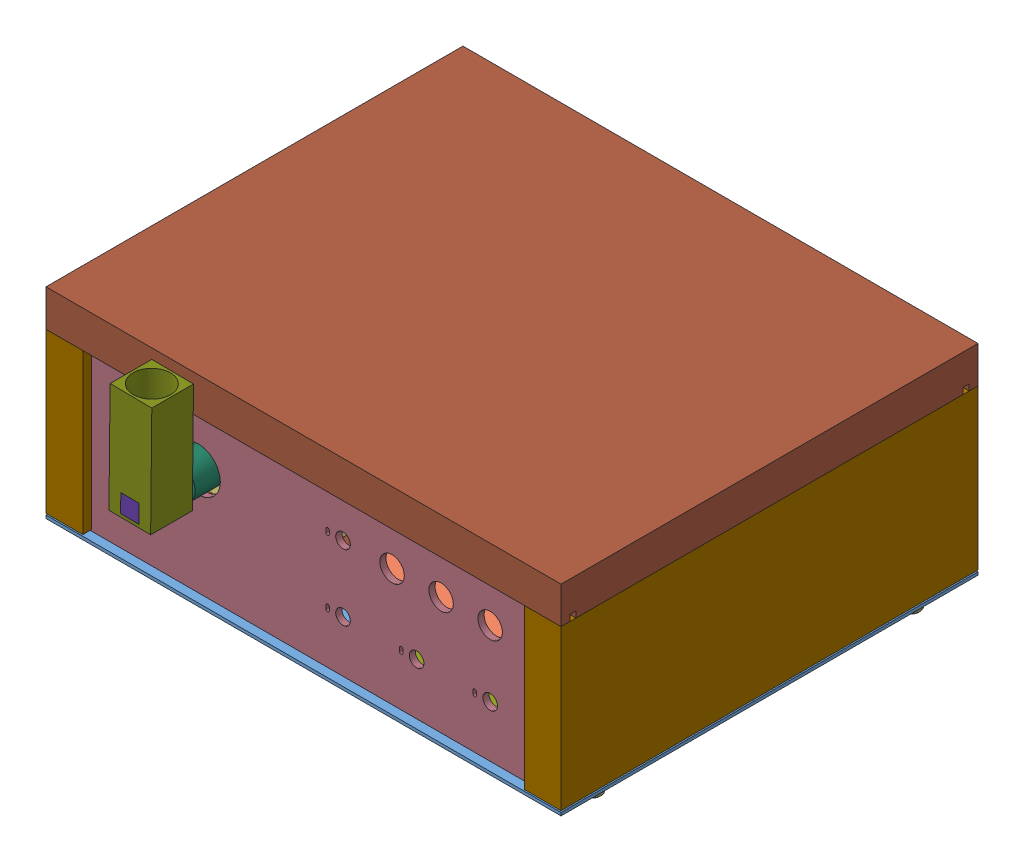
SolidWorks assembly Enclosure Assembly, configuration Default. Lengths in mm.
Overall size (266.7 114.51 246.61).
44 component instances, 21 part files, 71 mates.
Components (placement in the parent):
- Base Plate-1: Base Plate [Default] at (95.1379 143.2201 188.081) size (266.7 1.57 215.9)
- Driver Block-1: Driver Block [Default] at (35.9559 143.2201 203.5115) x (0 0 -1) z (1 0 0) size (130.18 25.4 76.2)
- Motor Mounting Assembly-1: Motor Mounting Assembly [Default] at (35.2898 189.415 201.5637) x (0 0 1) z (-1 0 0) size (444.54 56.1 76.2)
  - Motor Mount-1: Motor Mount [Default] at (1.9479 -20.7949 -0.6662) size (130.18 50.38 76.2)
  - Maxon Motor-1: Maxon Motor [Default] at (62.8204 9.2051 -0.6662) x (-1 0 0) z (0 0 -1) size (96.7 30 30)
  - Encoder Block-1: Encoder Block [Default] at (-24.3646 9.2051 -0.6662) x (0 0.000323 1) z (1 0 0) size (30 41.1 18.3)
  - 91274A103_Zinc-Aluminum-Coated Alloy Steel Socket Head Screw-1: 91274A103_Zinc-Aluminum-Coated Alloy Steel Socket Head Screw [91274A103] at (59.0354 20.2051 -0.6662) x (0 -0.151827 -0.988407) z (-1 0 0) size (5.5 5.5 11.2)
  - 91274A103_Zinc-Aluminum-Coated Alloy Steel Socket Head Screw-2: 91274A103_Zinc-Aluminum-Coated Alloy Steel Socket Head Screw [91274A103] at (59.0354 3.7051 8.8601) x (0 0 -1) z (-1 0 0) size (5.5 5.5 11.2)
  - 91274A103_Zinc-Aluminum-Coated Alloy Steel Socket Head Screw-3: 91274A103_Zinc-Aluminum-Coated Alloy Steel Socket Head Screw [91274A103] at (59.0354 3.7051 -10.1924) x (0 0 -1) z (-1 0 0) size (5.5 5.5 11.2)
  - 91274A103_Zinc-Aluminum-Coated Alloy Steel Socket Head Screw-4: 91274A103_Zinc-Aluminum-Coated Alloy Steel Socket Head Screw [91274A103] at (59.0354 14.7051 8.8601) x (0 0 -1) z (-1 0 0) size (5.5 5.5 11.2)
  - 91274A103_Zinc-Aluminum-Coated Alloy Steel Socket Head Screw-5: 91274A103_Zinc-Aluminum-Coated Alloy Steel Socket Head Screw [91274A103] at (59.0354 14.7051 -10.1924) x (0 0 -1) z (-1 0 0) size (5.5 5.5 11.2)
  - 91274A103_Zinc-Aluminum-Coated Alloy Steel Socket Head Screw-6: 91274A103_Zinc-Aluminum-Coated Alloy Steel Socket Head Screw [91274A103] at (59.0354 -1.7949 -0.6662) x (0 0 -1) z (-1 0 0) size (5.5 5.5 11.2)
- Power Supply Block-1: Power Supply Block [Default] at (153.9988 143.2201 194.109) x (-0.000272 0 -1) z (1 0 -0.000272) size (158.75 38.1 98.42)
- myRio Block-1: myRio Block [Default] at (151.3206 184.4951 195.7743) x (0 0 -1) z (1 0 0) size (136.53 25.4 88.9)
- Wood Side Piece-1: Wood Side Piece [Default] at (-38.2121 185.2571 188.081) x (0 0 -1) z (1 0 0) size (215.9 82.55 19.05)
- Wood Side Piece-2: Wood Side Piece [Default] at (228.4879 185.2571 188.081) x (0 0 1) z (-1 0 0) size (215.9 82.55 19.05)
- 97467A725_18-8 Stainless Steel Heavy-Duty Rivet Nut-1: 97467A725_18-8 Stainless Steel Heavy-Duty Rivet Nut [97467A725] at (218.9629 143.2201 270.631) x (-0.837169 0 -0.546944) z (-0.546944 0 0.837169) size (12.7 16 12.7)
- 97467A725_18-8 Stainless Steel Heavy-Duty Rivet Nut-2: 97467A725_18-8 Stainless Steel Heavy-Duty Rivet Nut [97467A725] at (218.9629 143.2201 105.531) x (-0.837169 0 -0.546944) z (-0.546944 0 0.837169) size (12.7 16 12.7)
- 97467A725_18-8 Stainless Steel Heavy-Duty Rivet Nut-3: 97467A725_18-8 Stainless Steel Heavy-Duty Rivet Nut [97467A725] at (-28.6871 143.2201 270.631) x (-0.837169 0 -0.546944) z (-0.546944 0 0.837169) size (12.7 16 12.7)
- 97467A725_18-8 Stainless Steel Heavy-Duty Rivet Nut-4: 97467A725_18-8 Stainless Steel Heavy-Duty Rivet Nut [97467A725] at (-28.6871 143.2201 105.531) x (-0.36154 0 0.932356) z (0.932356 0 0.36154) size (12.7 16 12.7)
- Wood Top Piece-1: Wood Top Piece [Default] at (95.1379 226.5321 188.081) size (266.7 19.05 215.9)
- 91274A160_Zinc-Aluminum-Coated Alloy Steel Socket Head Screw-1: 91274A160_Zinc-Aluminum-Coated Alloy Steel Socket Head Screw [91274A160] at (218.9629 157.5203 105.531) x (-0.902068 0 0.431594) z (0 1 0) size (9.53 9.53 22.9)
- 91274A160_Zinc-Aluminum-Coated Alloy Steel Socket Head Screw-2: 91274A160_Zinc-Aluminum-Coated Alloy Steel Socket Head Screw [91274A160] at (218.9629 157.5203 270.631) x (-0.803937 0 -0.594714) z (0 1 0) size (9.53 9.53 22.9)
- 91274A160_Zinc-Aluminum-Coated Alloy Steel Socket Head Screw-3: 91274A160_Zinc-Aluminum-Coated Alloy Steel Socket Head Screw [91274A160] at (-28.6871 157.5203 270.631) x (-0.882264 0 -0.470755) z (0 1 0) size (9.53 9.53 22.9)
- 91274A160_Zinc-Aluminum-Coated Alloy Steel Socket Head Screw-4: 91274A160_Zinc-Aluminum-Coated Alloy Steel Socket Head Screw [91274A160] at (-28.6871 157.5203 105.531) x (-0.849031 0 -0.528343) z (0 1 0) size (9.53 9.53 22.9)
- Front and Back Piece-1: Front and Back Piece [Default] at (95.1379 186.4001 291.459) size (234.95 86.36 3.17)
- Back Piece-1: Back Piece [Default] at (95.1379 186.4001 84.703) x (-1 0 0) z (0 0 -1) size (234.95 86.36 3.17)
- Coupler-1: Coupler [Default] at (35.9559 198.6201 289.479) x (-0.99356 -0.113306 0) z (0 0 -1) size (18 18 25)
- Pendulum Assembly-1: Pendulum Assembly [Default] at (10.9481 174.972 253.8303) x (0.999944 -0.01058 0) z (0 0 1) size (21.59 57.15 44.45)
  - Pendulum-1: Pendulum [Default] at (24.7562 17.5613 62.1187) size (21.59 57.15 21.59)
  - Pendulum Dowel-1: Pendulum Dowel [Default] at (24.7562 23.9113 66.5637) size (9.53 9.53 44.45)
- 90272A163_Zinc-Plated Steel Pan Head Phillips Screw-1: 90272A163_Zinc-Plated Steel Pan Head Phillips Screw [90272A163] at (63.3879 178.5134 142.742) x (1 0 0) z (0 -1 0) size (6.86 6.86 79.08)
- 90272A163_Zinc-Plated Steel Pan Head Phillips Screw-2: 90272A163_Zinc-Plated Steel Pan Head Phillips Screw [90272A163] at (12.5879 178.5134 264.281) x (1 0 0) z (0 -1 0) size (6.86 6.86 79.08)
- 90272A163_Zinc-Plated Steel Pan Head Phillips Screw-3: 90272A163_Zinc-Plated Steel Pan Head Phillips Screw [90272A163] at (12.5879 178.5134 142.742) x (1 0 0) z (0 -1 0) size (6.86 6.86 79.08)
- 90272A163_Zinc-Plated Steel Pan Head Phillips Screw-4: 90272A163_Zinc-Plated Steel Pan Head Phillips Screw [90272A163] at (63.3879 178.5134 264.281) x (1 0 0) z (0 -1 0) size (6.86 6.86 79.08)
- 90631A007_Low-Strength Steel Nylon-Insert Locknut-1: 90631A007_Low-Strength Steel Nylon-Insert Locknut [90631A007] at (63.3879 188.6201 142.742) size (7.94 4.48 9.17)
- 90631A007_Low-Strength Steel Nylon-Insert Locknut-2: 90631A007_Low-Strength Steel Nylon-Insert Locknut [90631A007] at (12.5879 188.6201 264.281) size (7.94 4.48 9.17)
- 90631A007_Low-Strength Steel Nylon-Insert Locknut-3: 90631A007_Low-Strength Steel Nylon-Insert Locknut [90631A007] at (63.3879 188.6201 264.281) size (7.94 4.48 9.17)
- 90631A007_Low-Strength Steel Nylon-Insert Locknut-4: 90631A007_Low-Strength Steel Nylon-Insert Locknut [90631A007] at (12.5879 188.6201 142.742) size (7.94 4.48 9.17)
- myRIO_Mounting_Plate V2-1: myRIO_Mounting_Plate V2 [Default] at (150.8238 181.3201 194.1099) x (-0.000272 0 -1) z (1 0 -0.000272) size (165.1 9.65 104.77)
- 90272A163_Zinc-Plated Steel Pan Head Phillips Screw-5: 90272A163_Zinc-Plated Steel Pan Head Phillips Screw [90272A163] at (194.4879 178.5134 270.031) x (1 0 0) z (0 -1 0) size (6.86 6.86 79.08)
- 90272A163_Zinc-Plated Steel Pan Head Phillips Screw-6: 90272A163_Zinc-Plated Steel Pan Head Phillips Screw [90272A163] at (111.4879 178.5134 117.131) x (1 0 0) z (0 -1 0) size (6.86 6.86 79.08)
- 90675A007_Steel Locknut with External-Tooth Lock Washer-1: 90675A007_Steel Locknut with External-Tooth Lock Washer [90675A007] at (194.4879 186.2731 270.031) x (0.908918 0 -0.416976) z (0 1 0) size (8.75 9.15 3.68)
- 90675A007_Steel Locknut with External-Tooth Lock Washer-2: 90675A007_Steel Locknut with External-Tooth Lock Washer [90675A007] at (111.4684 186.2731 117.1536) x (-0.80754 0 0.589813) z (0 1 0) size (8.75 9.15 3.68)
Mates (geometry in assembly coordinates):
- Coincident1: coincident anti-aligned: plane of Base Plate-1 through (95.1379 143.2201 188.081) normal (0 1 0); plane of Driver Block-1 through (35.9559 143.2201 203.5115) normal (0 -1 0)
- Coincident2: coincident anti-aligned: plane of Base Plate-1 through (95.1379 143.2201 188.081) normal (0 1 0); plane of Power Supply Block-1 through (153.9988 143.2201 194.109) normal (0 -1 0)
- Coincident4: coincident anti-aligned: plane of Driver Block-1 through (35.9559 168.6201 203.5115) normal (0 1 0); plane of Motor Mounting Assembly-1/Motor Mount-1 through (35.9559 168.6201 203.5115) normal (0 -1 0)
- Coincident5: coincident aligned: plane of Driver Block-1 through (74.0559 168.6201 268.599) normal (0 0 1); plane of Motor Mounting Assembly-1/Motor Mount-1 through (-2.1441 188.6201 268.599) normal (0 0 1)
- Concentric1: concentric anti-aligned: cylinder of Base Plate-1 through (-28.6871 130.4199 270.631) axis (0 1 0) radius 3.9688; cylinder of Wood Side Piece-1 through (-28.6871 163.0321 270.631) axis (0 -1 0) radius 4.7625
- Concentric2: concentric anti-aligned: cylinder of Base Plate-1 through (-28.6871 130.4199 105.531) axis (0 1 0) radius 3.9688; cylinder of Wood Side Piece-1 through (-28.6871 163.0321 105.531) axis (0 -1 0) radius 4.7625
- Concentric3: concentric anti-aligned: cylinder of Base Plate-1 through (218.9629 130.4199 270.631) axis (0 1 0) radius 3.9688; cylinder of Wood Side Piece-2 through (218.9629 163.0321 270.631) axis (0 -1 0) radius 4.7625
- Concentric4: concentric anti-aligned: cylinder of Base Plate-1 through (218.9629 130.4199 105.531) axis (0 1 0) radius 3.9688; cylinder of Wood Side Piece-2 through (218.9629 163.0321 105.531) axis (0 -1 0) radius 4.7625
- Coincident8: coincident anti-aligned: plane of Wood Side Piece-1 through (-19.1621 143.9821 296.031) normal (0 -1 0); plane of 97467A725_18-8 Stainless Steel Heavy-Duty Rivet Nut-3 through (-23.3711 143.9821 274.1041) normal (0 1 0)
- Concentric5: concentric aligned: cylinder of Wood Side Piece-1 through (-28.6871 163.0321 270.631) axis (0 -1 0) radius 4.7625; cylinder of 97467A725_18-8 Stainless Steel Heavy-Duty Rivet Nut-3 through (-28.6871 143.2201 270.631) axis (0 -1 0) radius 4.445
- Concentric6: concentric aligned: cylinder of Wood Side Piece-1 through (-28.6871 163.0321 105.531) axis (0 -1 0) radius 4.7625; cylinder of 97467A725_18-8 Stainless Steel Heavy-Duty Rivet Nut-4 through (-28.6871 143.2201 105.531) axis (0 -1 0) radius 4.445
- Coincident9: coincident aligned: plane of Wood Side Piece-1 through (-19.1621 143.9821 296.031) normal (0 -1 0); circle of 97467A725_18-8 Stainless Steel Heavy-Duty Rivet Nut-4
- Coincident10: coincident anti-aligned: plane of Wood Side Piece-2 through (209.4379 143.9821 80.131) normal (0 -1 0); plane of 97467A725_18-8 Stainless Steel Heavy-Duty Rivet Nut-1 through (224.2789 143.9821 274.1041) normal (0 1 0)
- Concentric7: concentric aligned: cylinder of Wood Side Piece-2 through (218.9629 163.0321 270.631) axis (0 -1 0) radius 4.7625; cylinder of 97467A725_18-8 Stainless Steel Heavy-Duty Rivet Nut-1 through (218.9629 143.2201 270.631) axis (0 -1 0) radius 4.445
- Coincident11: coincident anti-aligned: plane of Wood Side Piece-2 through (209.4379 143.9821 80.131) normal (0 -1 0); plane of 97467A725_18-8 Stainless Steel Heavy-Duty Rivet Nut-2 through (224.2789 143.9821 109.0041) normal (0 1 0)
- Concentric8: concentric aligned: circle of Wood Side Piece-2; cylinder of 97467A725_18-8 Stainless Steel Heavy-Duty Rivet Nut-2 through (218.9629 143.2201 105.531) axis (0 -1 0) radius 4.445
- Coincident12: coincident anti-aligned: plane of Base Plate-1 through (95.1379 143.2201 188.081) normal (0 1 0); plane of 97467A725_18-8 Stainless Steel Heavy-Duty Rivet Nut-1 through (222.6841 143.2201 273.0622) normal (0 -1 0)
- Coincident13: coincident anti-aligned: plane of Base Plate-1 through (95.1379 143.2201 188.081) normal (0 1 0); plane of 97467A725_18-8 Stainless Steel Heavy-Duty Rivet Nut-3 through (-24.9659 143.2201 273.0622) normal (0 -1 0)
- Coincident14: coincident anti-aligned: plane of Wood Side Piece-1 through (-19.1621 226.5321 296.031) normal (0 1 0); plane of Wood Top Piece-1 through (95.1379 226.5321 188.081) normal (0 -1 0)
- Coincident15: coincident aligned: plane of Wood Side Piece-1 through (-38.2121 185.2571 188.081) normal (-1 0 0); plane of Wood Top Piece-1 through (-38.2121 245.5821 296.031) normal (-1 0 0)
- Coincident16: coincident aligned: plane of Wood Side Piece-1 through (-19.1621 143.9821 296.031) normal (0 0 1); plane of Wood Top Piece-1 through (-38.2121 245.5821 296.031) normal (0 0 1)
- Concentric10: concentric aligned: cylinder of Base Plate-1 through (-28.6871 130.4199 270.631) axis (0 1 0) radius 3.9688; cylinder of 91274A160_Zinc-Aluminum-Coated Alloy Steel Socket Head Screw-3 through (-28.6871 135.2953 270.631) axis (0 1 0) radius 4.7625
- Coincident17: coincident anti-aligned: plane of Base Plate-1 through (95.1379 141.6453 188.081) normal (0 -1 0); plane of 91274A160_Zinc-Aluminum-Coated Alloy Steel Socket Head Screw-3 through (-28.6871 141.6453 270.631) normal (0 1 0)
- Concentric11: concentric aligned: cylinder of Base Plate-1 through (-28.6871 130.4199 105.531) axis (0 1 0) radius 3.9688; cylinder of 91274A160_Zinc-Aluminum-Coated Alloy Steel Socket Head Screw-4 through (-28.6871 135.2953 105.531) axis (0 1 0) radius 4.7625
- Coincident18: coincident anti-aligned: plane of Base Plate-1 through (95.1379 141.6453 188.081) normal (0 -1 0); plane of 91274A160_Zinc-Aluminum-Coated Alloy Steel Socket Head Screw-4 through (-28.6871 141.6453 105.531) normal (0 1 0)
- Concentric12: concentric aligned: cylinder of Base Plate-1 through (218.9629 130.4199 270.631) axis (0 1 0) radius 3.9688; cylinder of 91274A160_Zinc-Aluminum-Coated Alloy Steel Socket Head Screw-2 through (218.9629 135.2953 270.631) axis (0 1 0) radius 4.7625
- Coincident19: coincident anti-aligned: plane of Base Plate-1 through (95.1379 141.6453 188.081) normal (0 -1 0); plane of 91274A160_Zinc-Aluminum-Coated Alloy Steel Socket Head Screw-2 through (218.9629 141.6453 270.631) normal (0 1 0)
- Concentric13: concentric aligned: cylinder of Base Plate-1 through (218.9629 130.4199 105.531) axis (0 1 0) radius 3.9688; cylinder of 91274A160_Zinc-Aluminum-Coated Alloy Steel Socket Head Screw-1 through (218.9629 135.2953 105.531) axis (0 1 0) radius 4.7625
- Coincident20: coincident anti-aligned: plane of Base Plate-1 through (95.1379 141.6453 188.081) normal (0 -1 0); plane of 91274A160_Zinc-Aluminum-Coated Alloy Steel Socket Head Screw-1 through (218.9629 141.6453 105.531) normal (0 1 0)
- Coincident31: coincident aligned: plane of Driver Block-1 through (-2.1441 168.6201 268.599) normal (-1 0 0); plane of Motor Mounting Assembly-1/Motor Mount-1 through (-2.1441 188.6201 138.424) normal (-1 0 0)
- Coincident32: coincident anti-aligned: plane of Wood Side Piece-2 through (212.6129 226.5321 84.703) normal (-1 0 0); plane of Back Piece-1 through (212.6129 143.2201 87.878) normal (1 0 0)
- Coincident34: coincident aligned: cylinder of Motor Mounting Assembly-1/Maxon Motor-1 through (35.9559 198.6201 289.2415) axis (0 0 -1) radius 2.5; circle of Coupler-1
- Concentric15: concentric aligned: cylinder of Coupler-1 through (35.9559 198.6201 284.479) axis (0 0 1) radius 4; cylinder of Pendulum Assembly-1/Pendulum Dowel-1 through (35.9559 198.6201 282.294) axis (0 0 1) radius 2.8575
- Coincident35: coincident anti-aligned: plane of Base Plate-1 through (95.1379 141.6453 188.081) normal (0 -1 0); plane of 90272A163_Zinc-Plated Steel Pan Head Phillips Screw-2 through (15.8409 141.6453 264.281) normal (0 1 0)
- Concentric16: concentric aligned: circle of Motor Mounting Assembly-1/Motor Mount-1; circle of 90272A163_Zinc-Plated Steel Pan Head Phillips Screw-2
- Coincident37: coincident anti-aligned: plane of Base Plate-1 through (95.1379 141.6453 188.081) normal (0 -1 0); plane of 90272A163_Zinc-Plated Steel Pan Head Phillips Screw-4 through (66.6409 141.6453 264.281) normal (0 1 0)
- Concentric17: concentric aligned: circle of Motor Mounting Assembly-1/Motor Mount-1; circle of 90272A163_Zinc-Plated Steel Pan Head Phillips Screw-4
- Coincident38: coincident anti-aligned: plane of Base Plate-1 through (95.1379 141.6453 188.081) normal (0 -1 0); plane of 90272A163_Zinc-Plated Steel Pan Head Phillips Screw-3 through (15.8409 141.6453 142.742) normal (0 1 0)
- Concentric18: concentric anti-aligned: circle of Motor Mounting Assembly-1/Motor Mount-1; circle of 90272A163_Zinc-Plated Steel Pan Head Phillips Screw-3
- Coincident39: coincident anti-aligned: plane of Base Plate-1 through (95.1379 141.6453 188.081) normal (0 -1 0); plane of 90272A163_Zinc-Plated Steel Pan Head Phillips Screw-1 through (66.6409 141.6453 142.742) normal (0 1 0)
- Concentric19: concentric anti-aligned: circle of Motor Mounting Assembly-1/Motor Mount-1; circle of 90272A163_Zinc-Plated Steel Pan Head Phillips Screw-1
- Coincident40: coincident anti-aligned: plane of Motor Mounting Assembly-1/Motor Mount-1 through (35.9559 188.6201 203.5115) normal (0 1 0); plane of 90631A007_Low-Strength Steel Nylon-Insert Locknut-2 through (8.6192 188.6201 257.407) normal (0 -1 0)
- Concentric21: concentric aligned: circle of Motor Mounting Assembly-1/Motor Mount-1; circle of 90631A007_Low-Strength Steel Nylon-Insert Locknut-2
- Coincident41: coincident anti-aligned: plane of Motor Mounting Assembly-1/Motor Mount-1 through (35.9559 188.6201 203.5115) normal (0 1 0); plane of 90631A007_Low-Strength Steel Nylon-Insert Locknut-3 through (59.4192 188.6201 257.407) normal (0 -1 0)
- Concentric22: concentric aligned: circle of Motor Mounting Assembly-1/Motor Mount-1; circle of 90631A007_Low-Strength Steel Nylon-Insert Locknut-3
- Coincident42: coincident anti-aligned: plane of Motor Mounting Assembly-1/Motor Mount-1 through (35.9559 188.6201 203.5115) normal (0 1 0); plane of 90631A007_Low-Strength Steel Nylon-Insert Locknut-4 through (8.6192 188.6201 135.868) normal (0 -1 0)
- Concentric23: concentric anti-aligned: circle of Motor Mounting Assembly-1/Motor Mount-1; circle of 90631A007_Low-Strength Steel Nylon-Insert Locknut-4
- Coincident43: coincident anti-aligned: plane of Motor Mounting Assembly-1/Motor Mount-1 through (35.9559 188.6201 203.5115) normal (0 1 0); plane of 90631A007_Low-Strength Steel Nylon-Insert Locknut-1 through (59.4192 188.6201 135.868) normal (0 -1 0)
- Concentric24: concentric anti-aligned: circle of Motor Mounting Assembly-1/Motor Mount-1; circle of 90631A007_Low-Strength Steel Nylon-Insert Locknut-1
- Concentric39: concentric anti-aligned: circle of Base Plate-1; circle of Motor Mounting Assembly-1/Motor Mount-1
- Concentric40: concentric anti-aligned: circle of Base Plate-1; circle of Motor Mounting Assembly-1/Motor Mount-1
- Distance1: distance = 3.175 mm anti-aligned: plane of Coupler-1 through (35.9559 198.6201 301.979) normal (0 0 1); plane of Pendulum Assembly-1/Pendulum-1 through (25.699 249.5314 305.154) normal (0 0 -1)
- Distance2: distance = 7.62 mm anti-aligned: plane of Coupler-1 through (35.9559 198.6201 276.979) normal (0 0 -1); plane of Motor Mounting Assembly-1/Maxon Motor-1 through (35.9559 198.6201 284.599) normal (0 0 1)
- Coincident55: coincident anti-aligned: plane of Base Plate-1 through (95.1379 143.2201 188.081) normal (0 1 0); plane of Back Piece-1 through (212.6129 143.2201 87.878) normal (0 -1 0)
- Coincident56: coincident anti-aligned: plane of Wood Top Piece-1 through (-38.2121 226.5321 84.703) normal (0 0 1); plane of Back Piece-1 through (95.1379 186.4001 84.703) normal (0 0 -1)
- Coincident57: coincident anti-aligned: plane of Base Plate-1 through (95.1379 143.2201 188.081) normal (0 1 0); plane of Front and Back Piece-1 through (-22.3371 143.2201 288.284) normal (0 -1 0)
- Coincident58: coincident anti-aligned: plane of Wood Side Piece-2 through (212.6129 226.5321 291.459) normal (-1 0 0); plane of Front and Back Piece-1 through (212.6129 143.2201 288.284) normal (1 0 0)
- Coincident59: coincident anti-aligned: plane of Wood Top Piece-1 through (-38.2121 226.5321 291.459) normal (0 0 -1); plane of Front and Back Piece-1 through (95.1379 186.4001 291.459) normal (0 0 1)
- Coincident60: coincident anti-aligned: plane of Power Supply Block-1 through (153.9988 181.3201 194.109) normal (0 1 0); plane of myRIO_Mounting_Plate V2-1 through (150.8238 181.3201 194.1099) normal (0 -1 0)
- Coincident62: coincident aligned: plane of Power Supply Block-1 through (203.2328 181.3201 273.4707) normal (1 0 -0.000272); plane of myRIO_Mounting_Plate V2-1 through (203.2337 184.4951 276.6457) normal (1 0 -0.000272)
- Coincident63: coincident anti-aligned: plane of myRio Block-1 through (151.3206 184.4951 195.7743) normal (0 -1 0); plane of myRIO_Mounting_Plate V2-1 through (150.8238 184.4951 194.1099) normal (0 1 0)
- Distance3: distance = 3.175 mm aligned: plane of Power Supply Block-1 through (203.1897 181.3201 114.7207) normal (-0.000272 0 -1); plane of myRIO_Mounting_Plate V2-1 through (203.1888 184.4951 111.5457) normal (-0.000272 0 -1)
- Concentric41: concentric aligned: cylinder of Base Plate-1 through (194.4879 141.6453 270.031) axis (0 1 0) radius 2.3813; cylinder of myRIO_Mounting_Plate V2-1 through (194.4879 181.3201 270.031) axis (0 1 0) radius 2.3813
- Coincident64: coincident anti-aligned: plane of Base Plate-1 through (95.1379 141.6453 188.081) normal (0 -1 0); plane of 90272A163_Zinc-Plated Steel Pan Head Phillips Screw-5 through (197.7409 141.6453 270.031) normal (0 1 0)
- Concentric42: concentric anti-aligned: circle of Base Plate-1; circle of 90272A163_Zinc-Plated Steel Pan Head Phillips Screw-5
- Coincident65: coincident anti-aligned: plane of Base Plate-1 through (95.1379 141.6453 188.081) normal (0 -1 0); plane of 90272A163_Zinc-Plated Steel Pan Head Phillips Screw-6 through (114.7409 141.6453 117.131) normal (0 1 0)
- Concentric43: concentric anti-aligned: circle of Base Plate-1; circle of 90272A163_Zinc-Plated Steel Pan Head Phillips Screw-6
- Concentric44: concentric anti-aligned: circle of myRIO_Mounting_Plate V2-1; circle of 90675A007_Steel Locknut with External-Tooth Lock Washer-1
- Coincident66: coincident aligned: plane of myRIO_Mounting_Plate V2-1 through (150.8238 184.4951 194.1099) normal (0 1 0); circle of 90675A007_Steel Locknut with External-Tooth Lock Washer-1
- Concentric46: concentric anti-aligned: circle of myRIO_Mounting_Plate V2-1; circle of 90675A007_Steel Locknut with External-Tooth Lock Washer-2
- Coincident71: coincident aligned: plane of myRIO_Mounting_Plate V2-1 through (150.8238 184.4951 194.1099) normal (0 1 0); circle of 90675A007_Steel Locknut with External-Tooth Lock Washer-2
